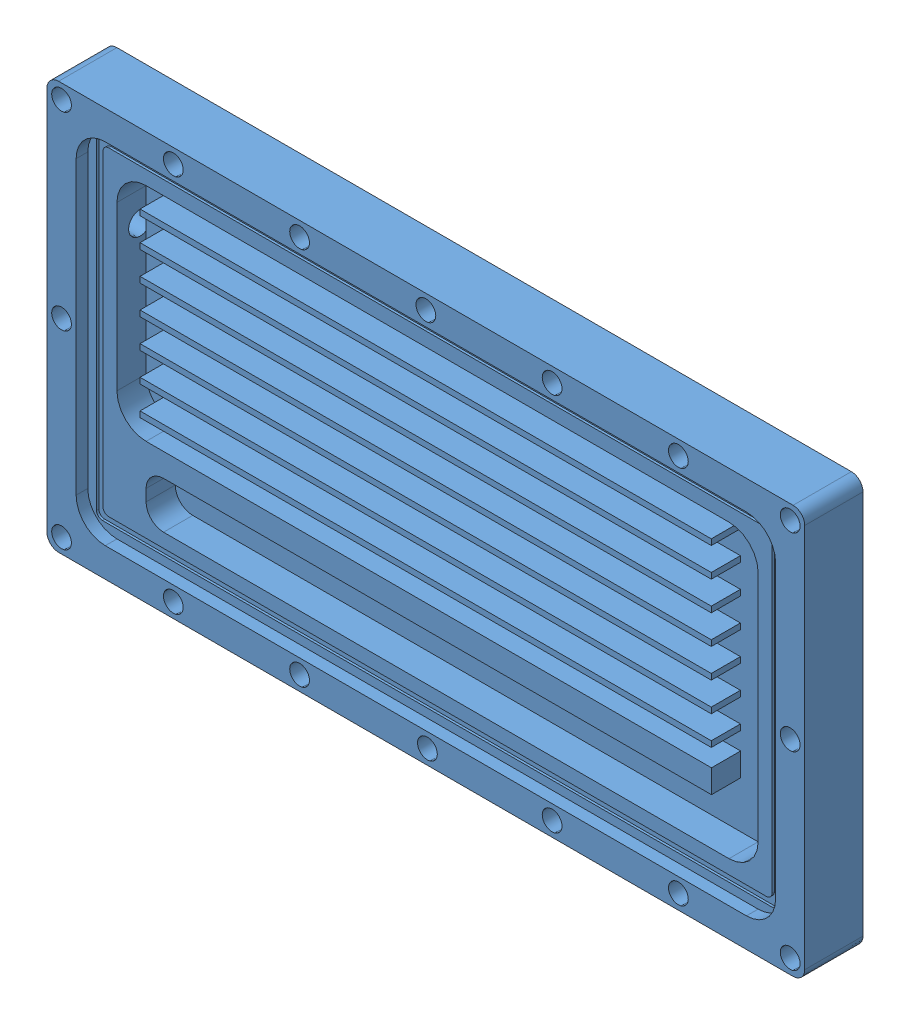
SolidWorks assembly Assemblage Watercooling C, configuration Défaut. Lengths in mm.
Overall size (130 70 11).
2 component instances, 2 part files, 3 mates.
Components (placement in the parent):
- EKO_Miner WaterBlock V1.0 C-1: EKO_Miner WaterBlock V1.0 C [Défaut] at (-83.6551 -26.0312 125) size (130 70 10)
- EKO_Miner WaterBlock V1.0 Couvercle-1: EKO_Miner WaterBlock V1.0 Couvercle [Défaut] at (-83.6551 43.9688 136) x (1 0 0) z (0 0 -1) size (130 70 3)
Mates (geometry in assembly coordinates):
- Coïncidente1: coincident aligned: plane of EKO_Miner WaterBlock V1.0 C-1 through (46.3449 -24.0312 135) normal (1 0 0); plane of EKO_Miner WaterBlock V1.0 Couvercle-1 through (46.3449 41.9688 135) normal (1 0 0)
- Coïncidente2: coincident aligned: plane of EKO_Miner WaterBlock V1.0 C-1 through (-81.6551 43.9688 135) normal (0 1 0); plane of EKO_Miner WaterBlock V1.0 Couvercle-1 through (-81.6551 43.9688 135) normal (0 1 0)
- Coïncidente3: coincident anti-aligned: plane of EKO_Miner WaterBlock V1.0 C-1 through (-81.6551 -24.0312 135) normal (0 0 1); plane of EKO_Miner WaterBlock V1.0 Couvercle-1 through (-81.6551 41.9688 135) normal (0 0 -1)
